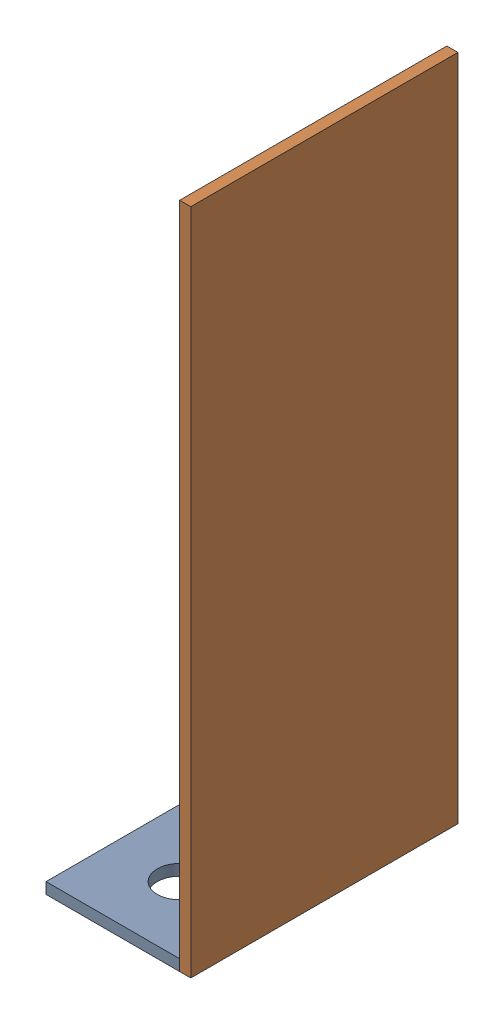
SolidWorks assembly 01-084-00-0, configuration Default. Lengths in mm.
Overall size (82.55 381 152.4).
3 component instances, 3 part files, 0 mates.
Components (placement in the parent):
- 01-083-00-0-1: 01-083-00-0 [Default] at (-41.8449 -4.93 79.3685) size (76.2 6.35 152.4)
- 01-081-00-0-1: 01-081-00-0 [Default] at (40.7051 -4.93 -73.0315) x (0 0 1) z (0 -1 0) size (152.4 6.35 381)
- 01-082-00-0-1: 01-082-00-0 [Default] at (-16.4449 1.42 -0.0065) x (1 0 0) z (0 -1 0) size (50.8 6.35 304.8)
